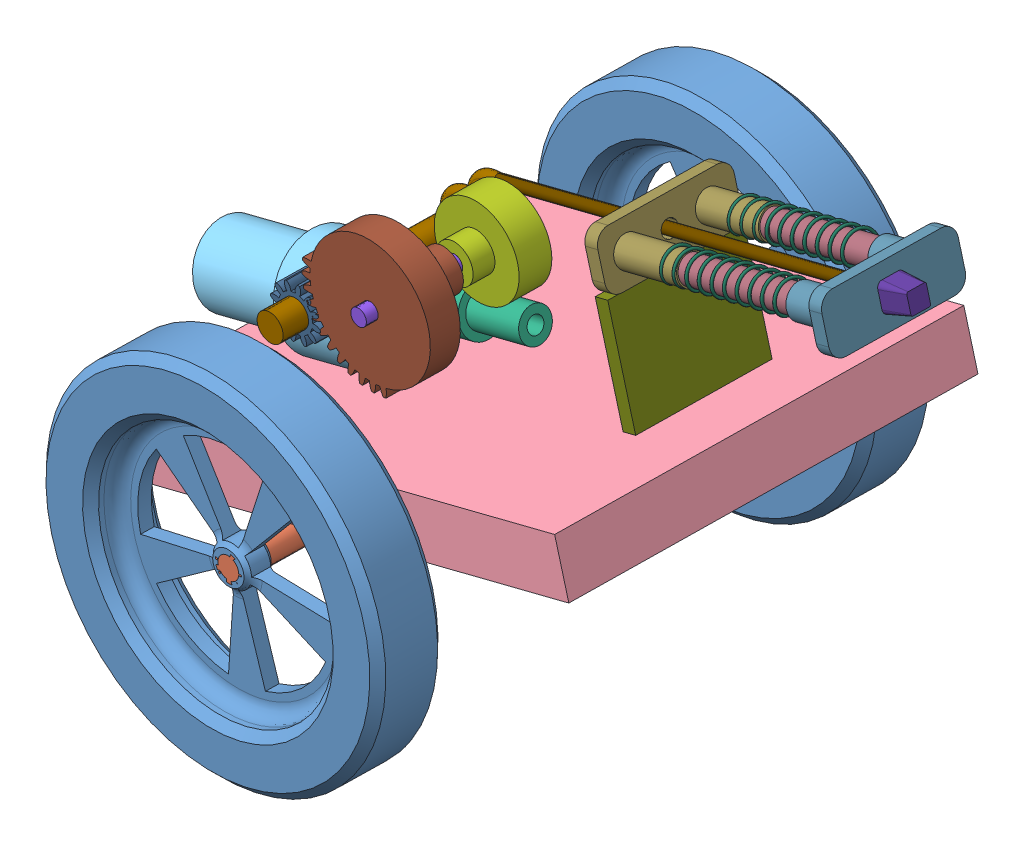
SolidWorks assembly hopbot, configuration Default. Lengths in mm.
Overall size (257.26 222.39 208.84).
25 component instances, 18 part files, 29 mates.
Components (placement in the parent):
- Wheel-1: Wheel [Default] at (153.0889 54.0501 242.6626) x (-0.591616 -0.806022 -0.017867) z (0.805928 -0.591853 0.013818) size (130 25 130)
- Wheel-2: Wheel [Default] at (156.9972 55.1705 62.7085) x (0.999531 -0.021713 0.021573) z (0.021573 0.999745 0.006693) size (130 25 130)
- axle-1: axle [Default] at (157.3772 55.2794 45.213) x (0.999697 0.011491 0.021783) z (-0.021713 -0.006224 0.999745) size (10 10 190)
- heavy duty external retaining ring_am-1: heavy duty external retaining ring_am [B27.8M - 3DM1-10] at (156.4001 54.9993 90.2015) x (-0.999426 0.026162 -0.021543) z (-0.021713 -0.006224 0.999745) size (12.01 13.7 0.9)
- heavy duty external retaining ring_am-2: heavy duty external retaining ring_am [B27.8M - 3DM1-10] at (154.2288 54.3769 190.176) x (0.933565 -0.357955 0.018047) z (0.021713 0.006224 -0.999745) size (12.01 13.7 0.9)
- base-1: base [Default] at (172.8306 85.6388 140.7619) x (-0.965028 -0.261173 -0.022585) z (0.261247 -0.965272 -0.000336) size (180 150 20.3)
- mech assss-2: mech assss [Default] at (19.8986 53.9094 179.9899) x (-0.021713 -0.006224 0.999745) z (0.965028 0.261173 0.022585) size (85 87.84 147.83)
  - motor 2-1: motor 2 [Default] at (-20.0328 -8.9413 64.9846) size (36.56 36.56 102.5)
  - worm gear part 1-1: worm gear part 1 [Default] at (-20.0328 -16.9313 156.9846) size (17.5 17.5 31)
  - worm gear part 2-1: worm gear part 2 [Default] at (-26.0328 -39.1813 177.2924) x (0 0 -1) z (1 0 0) size (32.5 32.5 20)
  - shaft between 2pi3 and wom-1: shaft between 2pi3 and wom [Default] at (-30.7361 -39.1813 177.2924) x (0 0.802001 0.597323) z (1 0 0) size (6 6 60)
  - pulley-2: pulley [Default] at (-44.3299 -25.0187 147.6459) x (-1 0 0) z (0 0.31071 -0.950505) size (85 19 19)
  - gears 1-1: gears 1 [Default] at (13.95 -59.0816 166.6961) x (0 0.790654 -0.612263) z (1 0 0) size (61.36 56.97 35)
    - spur gear_am-3: spur gear_am [Metric - Spur gear 1.375M 12T 14.5PA 11FW ---S12B8H27L6N] at (34.6667 0 11) x (0 0 -1) z (-0.999975 -0.007046 0) size (27 18.78 18.78)
    - big spur-1: big spur [Default] at (12.6363 23.1331 -6.996) x (0 0 1) z (0.98635 0.164665 0) size (27 49.1 49.1)
- assem3-1: assem3 [Default] at (243.7646 124.6731 228.6931) x (0.021713 0.006224 -0.999745) z (0.965028 0.261173 0.022585) size (50.03 20.07 94)
  - mount 1-1: mount 1 [Default] at (83.1556 34.1999 -20.6338) size (50 20 30)
  - mount 3-1: mount 3 [Default] at (74.1257 30.823 12.9837) x (0.99402 -0.109194 0) z (0 0 -1) size (9.6 9.6 49)
  - mount2-1: mount2 [Default] at (66.1694 39.939 73.3662) x (0.999999 -0.001471 0) z (0 0 -1) size (50 20 20)
  - spring-2: spring [Default] at (74.3292 31.0434 2.2218) x (0.374492 0.92723 0) z (0 0 1) size (13 13 51)
  - mount 3-2: mount 3 [Default] at (104.1257 30.823 12.9837) x (-0.689119 -0.724648 0) z (0 0 -1) size (9.6 9.6 49)
  - spring-3: spring [Default] at (104.4257 30.8209 -3.54) x (0.412087 0.911145 0) z (0 0 1) size (13 13 51)
- Part2-1: Part2 [Default] at (222.4251 130.961 143.5332) x (0.021713 0.006224 -0.999745) z (0.965028 0.261173 0.022585) size (50 40 5)
- Part3-1: Part3 [Default] at (308.2338 175.2683 137.3683) x (0.022097 0.004805 -0.999744) z (0.965028 0.261173 0.022585) size (10 10 10)
- Part4-1: Part4 [Default] at (157.4077 133.2646 137.7226) x (0.092862 -0.260011 -0.96113) z (0.965028 0.261173 0.022585) size (4 4 150)
Mates (geometry in assembly coordinates):
- Concentric1: concentric: cylinder of axle-1 through (153.2518 54.0968 235.1645) axis (0.021713 0.006224 -0.999745) radius 5; cylinder of heavy duty external retaining ring_am-2 through (154.2093 54.3713 191.0758) axis (0.021713 0.006224 -0.999745) radius 4.7
- Concentric2: concentric: cylinder of axle-1 through (153.2518 54.0968 235.1645) axis (0.021713 0.006224 -0.999745) radius 5; circle of heavy duty external retaining ring_am-1
- Concentric4: concentric: cylinder of Wheel-1 through (153.0889 54.0501 242.6626) axis (0.021713 0.006224 -0.999745) radius 4; cylinder of axle-1 through (153.2518 54.0968 235.1645) axis (0.021713 0.006224 -0.999745) radius 5
- Concentric5: concentric: cylinder of Wheel-2 through (156.9972 55.1705 62.7085) axis (0.021713 0.006224 -0.999745) radius 4; cylinder of axle-1 through (153.2518 54.0968 235.1645) axis (0.021713 0.006224 -0.999745) radius 5
- Coincident1: coincident: plane of Wheel-1 through (153.2518 54.0968 235.1645) normal (-0.021713 -0.006224 0.999745); plane of axle-1 through (153.2518 54.0968 235.1645) normal (-0.021713 -0.006224 0.999745)
- Coincident2: coincident: plane of Wheel-2 through (157.3772 55.2794 45.213) normal (0.021713 0.006224 -0.999745); plane of axle-1 through (157.3772 55.2794 45.213) normal (0.021713 0.006224 -0.999745)
- Distance1: distance = 35 mm: plane of heavy duty external retaining ring_am-2 through (154.2288 54.3769 190.176) normal (0.021713 0.006224 -0.999745); plane of Wheel-1 through (153.4689 54.159 225.1671) normal (0.021713 0.006224 -0.999745)
- Distance2: distance = 35 mm: plane of Wheel-2 through (157.16 55.2171 55.2104) normal (-0.021713 -0.006224 0.999745); plane of heavy duty external retaining ring_am-1 through (156.4001 54.9993 90.2015) normal (-0.021713 -0.006224 0.999745)
- Tangent1: tangent: cylinder of axle-1 through (153.2518 54.0968 235.1645) axis (0.021713 0.006224 -0.999745) radius 5; plane of base-1 through (178.1339 66.0438 140.755) normal (0.261247 -0.965272 -0.000336)
- Distance3: distance = 2.5 mm: plane of Wheel-2 through (156.9972 55.1705 62.7085) normal (-0.021713 -0.006224 0.999745); plane of base-1 through (266.6149 90.0161 67.8068) normal (0.021713 0.006224 -0.999745)
- Parallel2: parallel: plane of base-1 through (92.9099 43.005 63.7416) normal (-0.965028 -0.261173 -0.022585); plane of mech assss-2/motor 2-1 through (80.7096 79.6371 161.4329) normal (-0.965028 -0.261173 -0.022585)
- Tangent4: tangent: cylinder of Wheel-2 through (157.54 55.3261 37.7149) axis (-0.021713 -0.006224 0.999745) radius 65; plane of base-1 through (92.9099 43.005 63.7416) normal (-0.965028 -0.261173 -0.022585)
- Coincident8: coincident: plane of base-1 through (92.9099 43.005 63.7416) normal (-0.965028 -0.261173 -0.022585); plane of mech assss-2/motor 2-1 through (80.7096 79.6371 161.4329) normal (-0.965028 -0.261173 -0.022585)
- Tangent5: tangent: plane of base-1 through (172.8306 85.6388 140.7619) normal (-0.261247 0.965272 0.000336); cylinder of mech assss-2/motor 2-1 through (140.5413 95.8298 162.8332) axis (-0.965028 -0.261173 -0.022585) radius 18.28
- Parallel3: parallel: line of base-1 through (261.3116 109.6111 67.8136) axis (-0.021713 -0.006224 0.999745); cylinder of mech assss-2/shaft between 2pi3 and wom-1 through (180.1193 137.8518 213.2636) axis (0.021713 0.006224 -0.999745) radius 3
- Distance5: distance = 8 mm: line of assembly; plane of mech assss-2/pulley-2 through (156.9466 116.9361 132.6097) normal (0.021713 0.006224 -0.999745)
- Parallel4: parallel: plane of base-1 through (266.6149 90.0161 67.8068) normal (0.965028 0.261173 0.022585); plane of assem3-1/mount2-1 through (305.5678 182.7982 164.211) normal (0.965028 0.261173 0.022585)
- Parallel5: parallel: plane of base-1 through (172.8306 85.6388 140.7619) normal (-0.261247 0.965272 0.000336); plane of assem3-1/mount 1-1 through (224.7385 141.1201 159.239) normal (0.261247 -0.965272 -0.000336)
- Distance6: distance = 40 mm: plane of assem3-1/mount 1-1 through (224.7385 141.1201 159.239) normal (0.261247 -0.965272 -0.000336); plane of base-1 through (172.8306 85.6388 140.7619) normal (-0.261247 0.965272 0.000336)
- Distance7: distance = 20 mm: plane of mech assss-2/pulley-2 through (156.9466 116.9361 132.6097) normal (0.021713 0.006224 -0.999745); plane of assem3-1/mount 1-1 through (221.7968 155.8792 114.2555) normal (0.021713 0.006224 -0.999745)
- Coincident17: coincident: plane of base-1 through (266.6149 90.0161 67.8068) normal (0.965028 0.261173 0.022585); circle of assem3-1/mount 1-1
- Parallel7: parallel: line of base-1 through (261.3116 109.6111 67.8136) axis (-0.021713 -0.006224 0.999745); line of Part2-1 through (230.0226 101.1094 164.1059) axis (0.021713 0.006224 -0.999745)
- Coincident22: coincident: plane of assem3-1/mount 1-1 through (224.7385 141.1201 159.239) normal (0.261247 -0.965272 -0.000336); plane of Part2-1 through (224.3979 141.0262 164.2322) normal (-0.261247 0.965272 0.000336)
- Coincident23: coincident: plane of assem3-1/mount 1-1 through (221.7968 155.8792 114.2555) normal (0.021713 0.006224 -0.999745); plane of Part2-1 through (225.4835 141.3374 114.245) normal (0.021713 0.006224 -0.999745)
- Coincident24: coincident: plane of assem3-1/mount2-1 through (305.5678 182.7982 164.211) normal (0.965028 0.261173 0.022585); plane of Part3-1 through (308.2338 175.2683 137.3683) normal (-0.965028 -0.261173 -0.022585)
- Distance9: distance = 5 mm: line of assem3-1/mount2-1 through (305.3873 183.7345 161.0939) axis (0.022097 0.004805 -0.999744); line of Part3-1 through (307.0656 178.9891 144.2595) axis (0.022097 0.004805 -0.999744)
- Distance10: distance = 20 mm: line of Part3-1 through (307.7627 177.1053 136.2553) axis (0.261214 -0.96528 0.001134); line of assem3-1/mount2-1 through (310.2966 169.4708 116.2695) axis (-0.261214 0.96528 -0.001134)
- Tangent6: tangent: cylinder of mech assss-2/pulley-2 through (153.21 122.8194 127.9346) axis (0.021713 0.006224 -0.999745) radius 7; plane of Part4-1 through (157.4077 133.2646 137.7226) normal (-0.965028 -0.261173 -0.022585)
- Concentric6: concentric: cylinder of assem3-1/mount 1-1 through (222.5602 150.8973 139.2474) axis (-0.965028 -0.261173 -0.022585) radius 3; cylinder of Part4-1 through (302.1619 172.4405 141.1103) axis (-0.965028 -0.261173 -0.022585) radius 2
